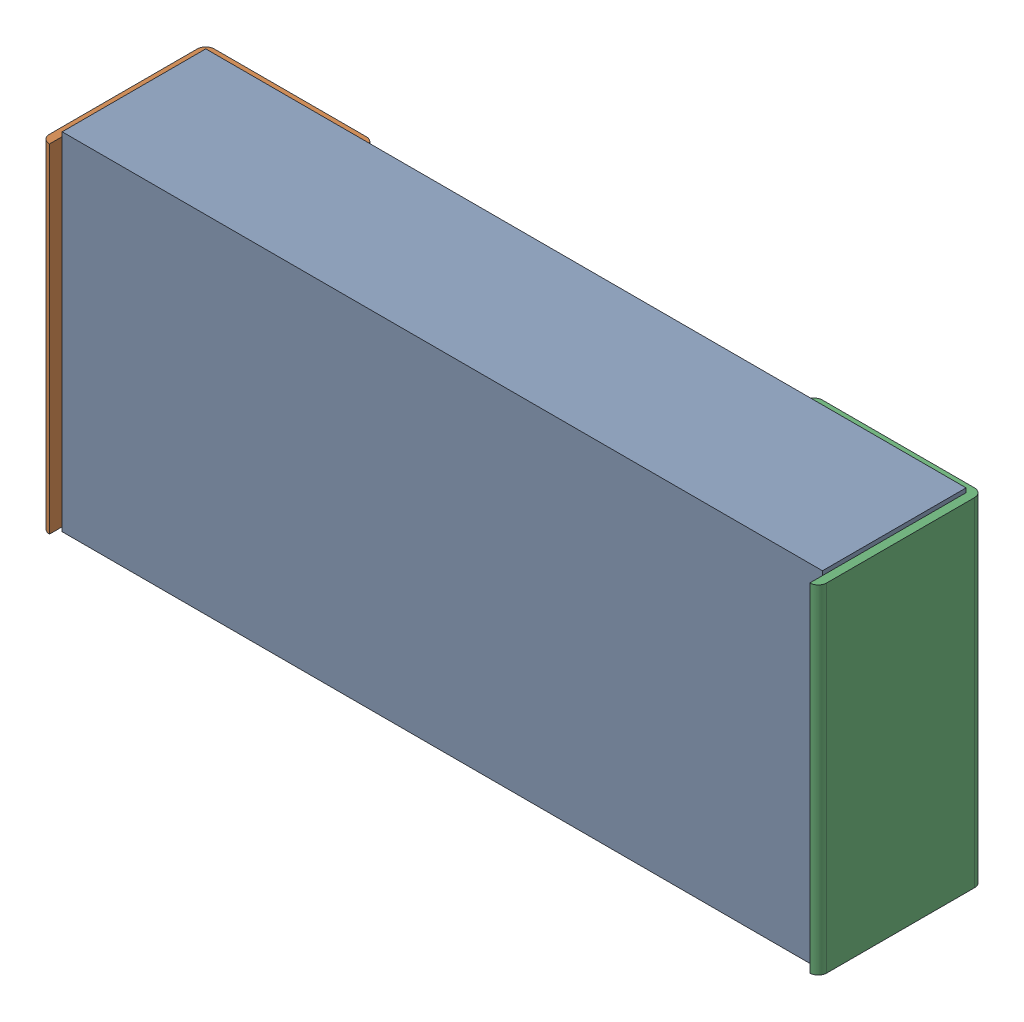
SolidWorks assembly Open CASCADE STEP translator 6.8 1.13.1, configuration Predeterminado. Lengths in mm.
Overall size (2.34 1.04 0.5).
3 component instances, 3 part files, 0 mates.
Components (placement in the parent):
- Body_1_5-1: Body_1_5 [Predeterminado] at origin size (2.29 1.04 0.43)
- Pin_1_4-1: Pin_1_4 [Predeterminado] at (0.3048 0 0) x (-1 0 0) z (0 0 1) size (0.51 1.02 0.5)
- Pin_2_4-1: Pin_2_4 [Predeterminado] at origin size (0.51 1.02 0.5)
